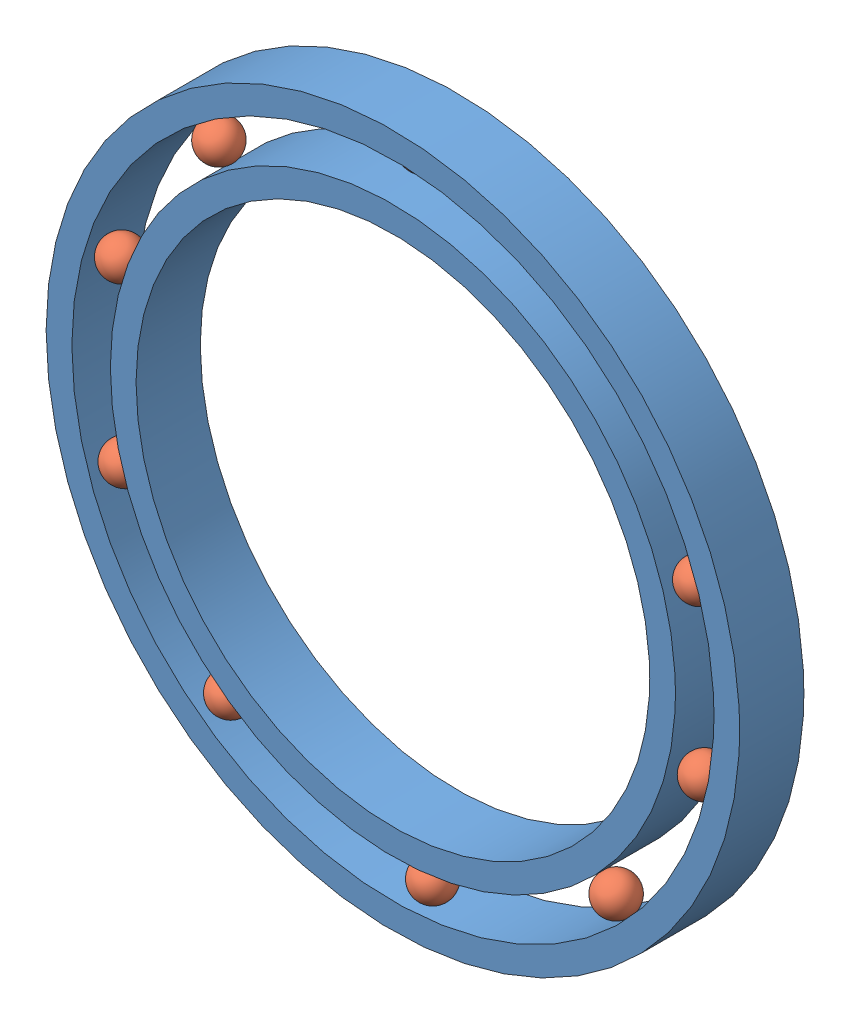
SolidWorks assembly Assem2, configuration Default. Lengths in mm.
Overall size (54 54 6.66).
11 component instances, 2 part files, 33 mates.
Components (placement in the parent):
- part1-1: part1 [Default] at (16.9178 32.5498 37.6901) size (54 54 5)
- Part2-1: Part2 [Default] at (15.7988 56.0232 39.1901) x (0.695893 -0.715494 0.061661) z (-0.608878 -0.542305 0.57894) size (3 3 3)
- Part2-3: Part2 [Default] at (30.7603 51.5402 39.1901) x (0.103388 0.325469 -0.939884) z (-0.992295 -0.031114 -0.119927) size (3 3 3)
- Part2-4: Part2 [Default] at (39.3087 39.6842 41.1901) x (-0.310301 -0.537174 -0.784319) z (0.92301 0.027217 -0.383812) size (3 3 3)
- Part2-5: Part2 [Default] at (-5.7008 38.9254 41.1901) x (0.936185 -0.169832 -0.307758) z (0.32567 0.089599 0.941229) size (3 3 3)
- Part2-6: Part2 [Default] at (32.8009 15.23 41.1901) x (0.614183 0.637295 -0.46544) z (-0.140496 -0.492065 -0.859147) size (3 3 3)
- Part2-8: Part2 [Default] at (18.521 9.1046 41.1901) x (-0.315573 -0.348284 -0.882673) z (-0.47525 0.86314 -0.170665) size (3 3 3)
- Part2-10: Part2 [Default] at (1.8711 50.601 41.1901) x (0.948163 0.311723 0.061777) z (-0.081665 0.051141 0.995347) size (3 3 3)
- Part2-11: Part2 [Default] at (39.6779 26.6993 41.1901) x (0.946732 0.243084 -0.211208) z (-0.04215 0.74378 0.667094) size (3 3 3)
- Part2-12: Part2 [Default] at (-5.4262 25.2699 41.1901) x (0.902415 -0.200103 0.381583) z (-0.429183 -0.339219 0.837098) size (3 3 3)
- Part2-13: Part2 [Default] at (2.7917 13.7694 41.1901) x (0.827852 0.035551 0.559819) z (-0.550532 -0.139921 0.823004) size (3 3 3)
Mates (geometry in assembly coordinates):
- Tangent3: tangent: cylinder of part1-1 through (16.9178 32.5498 42.6901) axis (0 0 -1) radius 25; sphere of Part2-1
- Tangent4: tangent aligned: cylinder of part1-1 through (16.9178 32.5498 42.6901) axis (0 0 -1) radius 25; sphere of Part2-3
- Tangent6: tangent aligned: plane of part1-1 through (16.9178 32.5498 37.6901) normal (0 0 -1); sphere of Part2-3
- Tangent12: tangent: cylinder of part1-1 through (16.9178 32.5498 42.6901) axis (0 0 -1) radius 25; sphere of Part2-1
- Tangent13: tangent: plane of part1-1 through (16.9178 32.5498 37.6901) normal (0 0 -1); sphere of Part2-1
- Tangent14: tangent aligned: cylinder of part1-1 through (16.9178 32.5498 42.6901) axis (0 0 -1) radius 25; sphere of Part2-4
- Tangent15: tangent aligned: plane of part1-1 through (16.9178 32.5498 42.6901) normal (0 0 1); sphere of Part2-4
- Tangent16: tangent aligned: cylinder of part1-1 through (16.9178 32.5498 42.6901) axis (0 0 -1) radius 25; sphere of Part2-8
- Tangent17: tangent aligned: plane of part1-1 through (16.9178 32.5498 42.6901) normal (0 0 1); sphere of Part2-8
- Tangent22: tangent aligned: cylinder of part1-1 through (16.9178 32.5498 42.6901) axis (0 0 -1) radius 25; sphere of Part2-6
- Tangent23: tangent aligned: plane of part1-1 through (16.9178 32.5498 42.6901) normal (0 0 1); sphere of Part2-6
- Tangent24: tangent aligned: cylinder of part1-1 through (16.9178 32.5498 42.6901) axis (0 0 -1) radius 25; sphere of Part2-5
- Tangent25: tangent aligned: plane of part1-1 through (16.9178 32.5498 42.6901) normal (0 0 1); sphere of Part2-5
- Tangent28: tangent anti-aligned: cylinder of part1-1 through (16.9178 32.5498 42.6901) axis (0 0 -1) radius 22; sphere of Part2-13
- Tangent29: tangent aligned: plane of part1-1 through (16.9178 32.5498 42.6901) normal (0 0 1); sphere of Part2-13
- Tangent30: tangent anti-aligned: cylinder of part1-1 through (16.9178 32.5498 42.6901) axis (0 0 -1) radius 22; sphere of Part2-12
- Tangent31: tangent aligned: plane of part1-1 through (16.9178 32.5498 42.6901) normal (0 0 1); sphere of Part2-12
- Tangent32: tangent anti-aligned: cylinder of part1-1 through (16.9178 32.5498 42.6901) axis (0 0 -1) radius 22; sphere of Part2-10
- Tangent33: tangent aligned: plane of part1-1 through (16.9178 32.5498 42.6901) normal (0 0 1); sphere of Part2-10
- Tangent34: tangent aligned: plane of part1-1 through (16.9178 32.5498 42.6901) normal (0 0 1); sphere of Part2-6
- Tangent35: tangent anti-aligned: cylinder of part1-1 through (16.9178 32.5498 42.6901) axis (0 0 -1) radius 22; sphere of Part2-6
- Tangent36: tangent aligned: cylinder of part1-1 through (16.9178 32.5498 42.6901) axis (0 0 -1) radius 25; sphere of Part2-11
- Tangent37: tangent aligned: plane of part1-1 through (16.9178 32.5498 42.6901) normal (0 0 1); sphere of Part2-11
- Lock1: lock: unknown of part1-1; unknown of Part2-10
- Lock2: lock: unknown of part1-1; unknown of Part2-5
- Lock3: lock: unknown of part1-1; unknown of Part2-12
- Lock4: lock: unknown of part1-1; unknown of Part2-13
- Lock5: lock: unknown of part1-1; unknown of Part2-8
- Lock6: lock: unknown of part1-1; unknown of Part2-6
- Lock7: lock: unknown of part1-1; unknown of Part2-11
- Lock8: lock: unknown of part1-1; unknown of Part2-4
- Lock9: lock: unknown of part1-1; unknown of Part2-3
- Lock10: lock: unknown of part1-1; unknown of Part2-1
